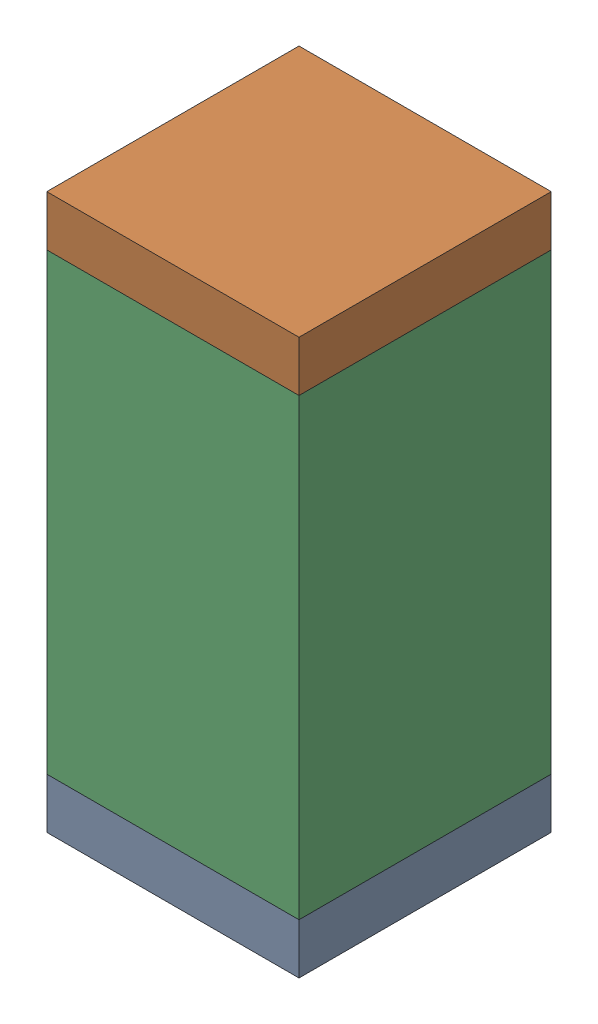
SolidWorks assembly C68, configuration Default. Lengths in mm.
Overall size (0.5 1.1 0.5).
6 component instances, 2 part files, 0 mates.
Components (placement in the parent):
- 810157360-1: 810157360 [Default] at (117.05 55.3 0) size (0.5 0.1 0.5)
  - Extruded_9-1: Extruded_9 [Default] at origin size (0.5 0.1 0.5)
- 810157360-2: 810157360 [Default] at (117.05 56.3 0) size (0.5 0.1 0.5)
  - Extruded_9-1: Extruded_9 [Default] at origin size (0.5 0.1 0.5)
- 791586336-1: 791586336 [Default] at (117.05 55.8 0) size (0.5 0.9 0.5)
  - Extruded_8-1: Extruded_8 [Default] at origin size (0.5 0.9 0.5)
